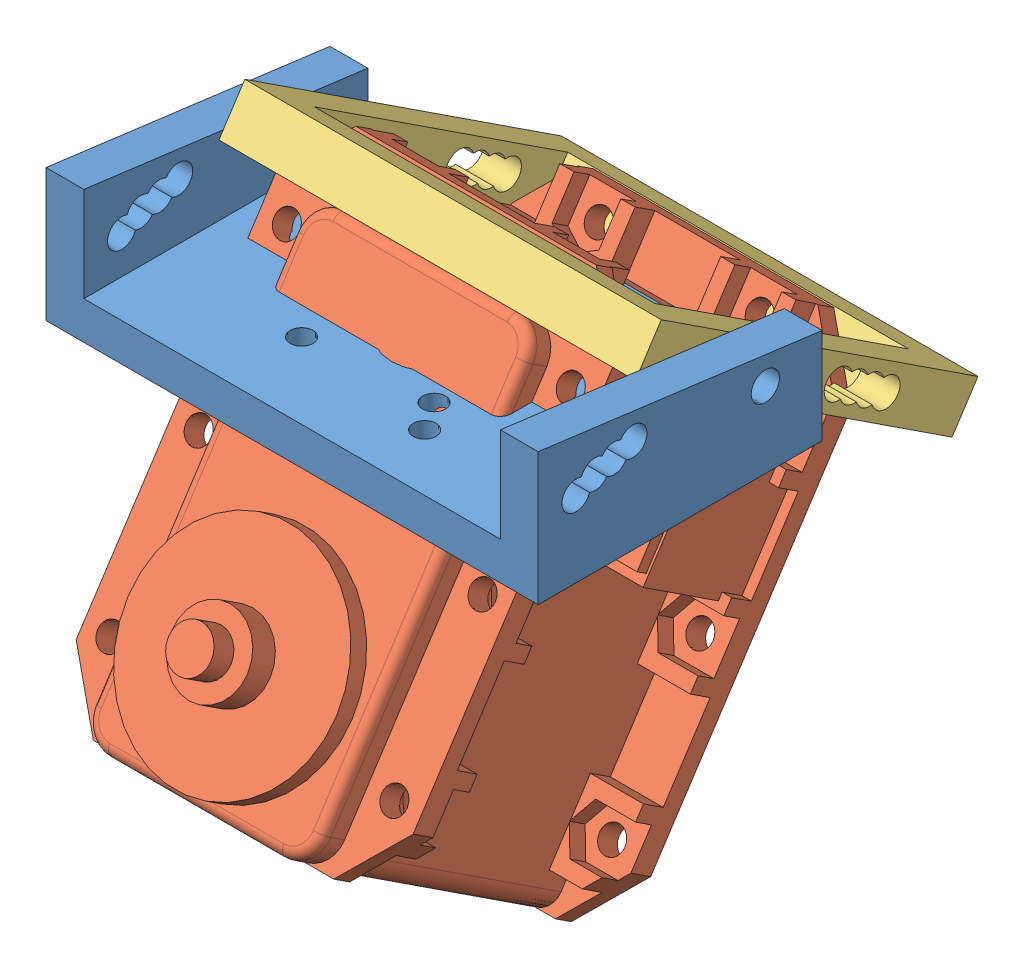
SolidWorks assembly Montagem1, configuration Valor predeterminado. Lengths in mm.
Overall size (52 68.99 68.36).
3 component instances, 3 part files, 4 mates.
Components (placement in the parent):
- suporte_inclinado_base_2-1: suporte_inclinado_base_2 [Valor predeterminado] at (-6.167 -4.8324 43) size (52 14 30)
- servo_rx24F-1: servo_rx24F [Valor predeterminado] at (-7.2541 -33.7103 46.0903) x (-1 0 0) z (0 0.548006 0.836474) size (35.6 50.71 48.5)
- suporte_inclinado_haste_2-1: suporte_inclinado_haste_2 [Valor predeterminado] at (-24.167 -4.3125 25.6353) x (0 -0.548006 -0.836474) z (-1 0 0) size (40 5 44)
Mates (geometry in assembly coordinates):
- Concêntrico1: concentric aligned: circle of servo_rx24F-1; circle of suporte_inclinado_haste_2-1
- Coincidente3: coincident anti-aligned: plane of servo_rx24F-1 through (-7.2541 -25.4902 58.6375) normal (0 0.548006 0.836474); plane of suporte_inclinado_haste_2-1 through (15.833 6.5468 37.6488) normal (0 -0.548006 -0.836474)
- Concêntrico3: concentric aligned: circle of servo_rx24F-1; circle of suporte_inclinado_haste_2-1
- Coincidente6: coincident aligned: circle of suporte_inclinado_base_2-1; circle of suporte_inclinado_haste_2-1
